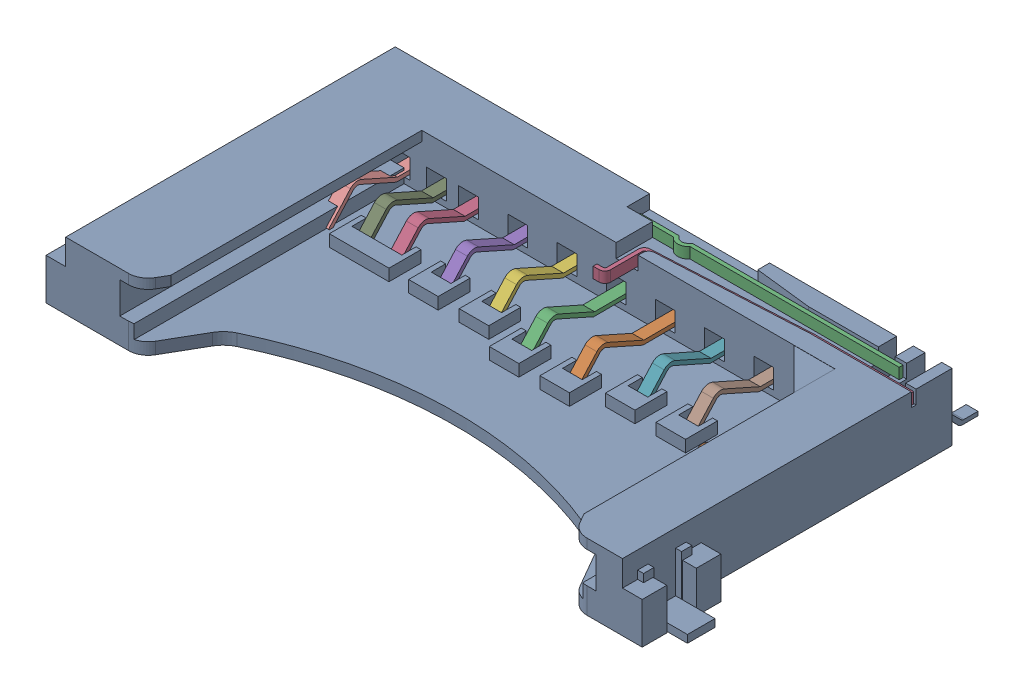
SolidWorks assembly raspberry_pi__SD_reader_assembly, configuration Default. Lengths in mm.
Overall size (32.3 4.2 18.72).
16 component instances, 6 part files, 0 mates.
Components (placement in the parent):
- raspberry_pi__SD_reader_body-1: raspberry_pi__SD_reader_body [Default] at (-67.8965 -2.1406 21.2643) size (32.3 4.2 16.75)
- raspberry_pi__SD_reader_pin1-1: raspberry_pi__SD_reader_pin1 [Default] at (-66.0305 -2.1406 -4.4304) x (0 0 -1) z (1 0 0) size (9.85 2.04 0.6)
- raspberry_pi__SD_reader_pin1-2: raspberry_pi__SD_reader_pin1 [Default] at (-68.5305 -2.1406 -4.4304) x (0 0 -1) z (1 0 0) size (9.85 2.04 0.6)
- raspberry_pi__SD_reader_pin2-1: raspberry_pi__SD_reader_pin2 [Default] at (-76.0205 -2.1385 -5.3387) x (0 0 -1) z (1 0 0) size (8.94 2.04 0.6)
- raspberry_pi__SD_reader_pin2-2: raspberry_pi__SD_reader_pin2 [Default] at (-73.5205 -2.1385 -5.3387) x (0 0 -1) z (1 0 0) size (8.94 2.04 0.6)
- raspberry_pi__SD_reader_pin2-3: raspberry_pi__SD_reader_pin2 [Default] at (-71.0205 -2.1385 -5.3387) x (0 0 -1) z (1 0 0) size (8.94 2.04 0.6)
- raspberry_pi__SD_reader_pin2-4: raspberry_pi__SD_reader_pin2 [Default] at (-63.5205 -2.1385 -5.3387) x (0 0 -1) z (1 0 0) size (8.94 2.04 0.6)
- raspberry_pi__SD_reader_pin2-5: raspberry_pi__SD_reader_pin2 [Default] at (-61.0205 -2.1385 -5.3387) x (0 0 -1) z (1 0 0) size (8.94 2.04 0.6)
- raspberry_pi__SD_reader_pin2-6: raspberry_pi__SD_reader_pin2 [Default] at (-77.6455 -2.1385 -5.3387) x (0 0 -1) z (1 0 0) size (8.94 2.04 0.6)
- raspberry_pi__SD_reader_pin2-7: raspberry_pi__SD_reader_pin2 [Default] at (-79.4655 -2.1385 -5.3387) x (0 0 -1) z (1 0 0) size (8.94 2.04 0.6)
- raspberry_pi__SD_reader_pin2-8: raspberry_pi__SD_reader_pin2 [Default] at (-81.1155 -2.1385 -5.3387) x (0 0 -1) z (1 0 0) size (8.94 2.04 0.6)
- raspberry_pi__SD_reader_pin2-9: raspberry_pi__SD_reader_pin2 [Default] at (-56.8355 -2.1385 -5.3387) x (0 0 -1) z (1 0 0) size (8.94 2.04 0.6)
- raspberry_pi__SD_reader_pin2-10: raspberry_pi__SD_reader_pin2 [Default] at (-55.3955 -2.1385 -5.3387) x (0 0 -1) z (1 0 0) size (8.94 2.04 0.6)
- raspberry_pi__SD_reader_pin3-1: raspberry_pi__SD_reader_pin3 [Default] at (-58.5401 -2.1448 -2.5387) x (0 0 -1) z (1 0 0) size (11.74 2.04 0.6)
- raspberry_pi__SD_reader_pin4-1: raspberry_pi__SD_reader_pin4 [Default] at (-62.6615 0.5594 -20.2143) x (1 0 0) z (0 1 0) size (13.35 0.4 0.55)
- raspberry_pi__SD_reader_pin5-1: raspberry_pi__SD_reader_pin5 [Default] at (-67.8965 0.5594 -4.5143) x (1 0 0) z (0 1 0) size (13.67 2.63 0.55)
